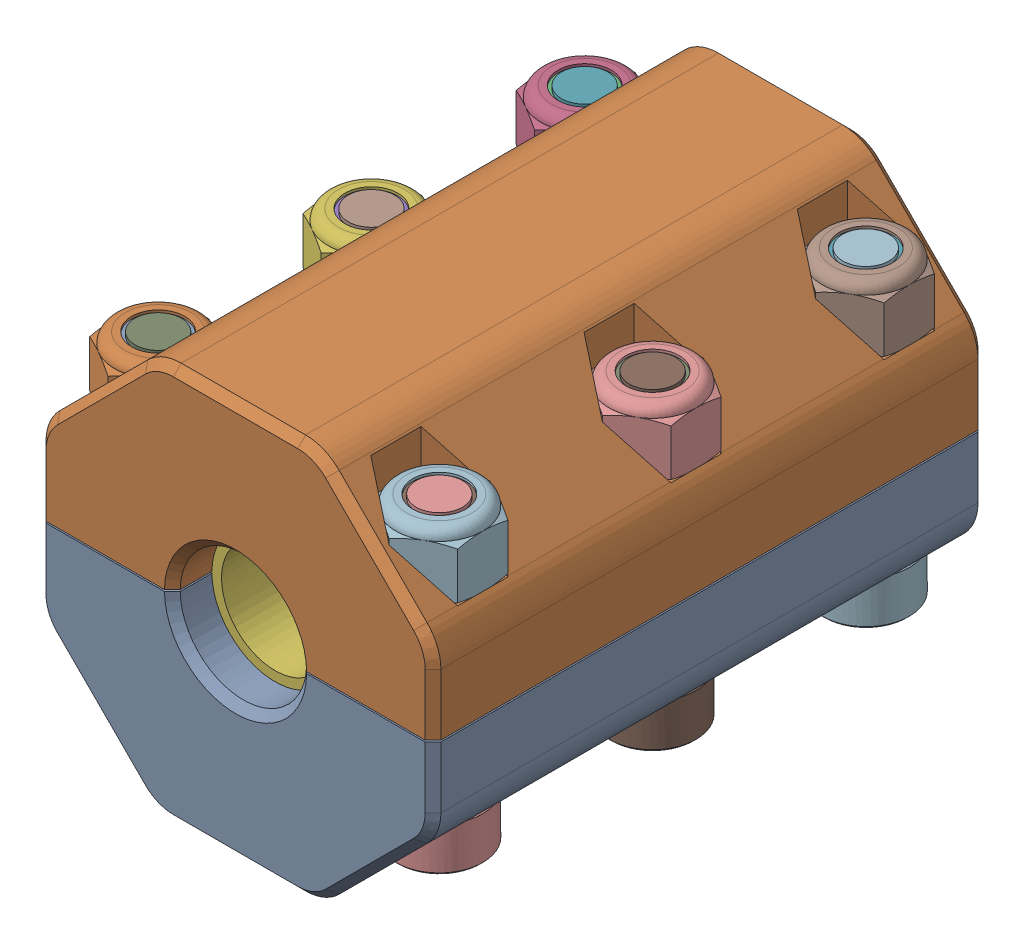
SolidWorks assembly 8mm Smooth to Threaded Shaft Coupler, configuration Default. Lengths in mm.
Overall size (25 25 35).
17 component instances, 6 part files, 0 mates.
Components (placement in the parent):
- 8mm Threaded to Smooth Coupler Shell A-1: 8mm Threaded to Smooth Coupler Shell A [Default] at origin size (25 12.45 35)
- 8mm Threaded to Smooth Coupler Shell B-1: 8mm Threaded to Smooth Coupler Shell B [Default] at origin size (25 12.45 35)
- 57485K67-1: 57485K67 [57485K67] at (0 0 6.5) x (-1 0 0) z (0 0 1) size (16 16 8)
- M8 x 1.25 Hex Nut-1: M8 x 1.25 Hex Nut [Default] at (0 0 20.75) size (13 15.01 6.5)
- M8 x 1.25 Hex Nut-2: M8 x 1.25 Hex Nut [Default] at (0 0 29.25) size (13 15.01 6.5)
- M3 x 0.5 Lock Nut-1: M3 x 0.5 Lock Nut [Default] at (8.9 6 4) x (1 0 0) z (0 1 0) size (5.5 6.35 4)
- M3 x 0.5 Lock Nut-2: M3 x 0.5 Lock Nut [Default] at (8.9 6 17.5) x (1 0 0) z (0 1 0) size (5.5 6.35 4)
- M3 x 0.5 Lock Nut-3: M3 x 0.5 Lock Nut [Default] at (8.9 6 31) x (1 0 0) z (0 1 0) size (5.5 6.35 4)
- M3 x 0.5 Lock Nut-4: M3 x 0.5 Lock Nut [Default] at (-8.9 6 31) x (1 0 0) z (0 1 0) size (5.5 6.35 4)
- M3 x 0.5 Lock Nut-5: M3 x 0.5 Lock Nut [Default] at (-8.9 6 4) x (1 0 0) z (0 1 0) size (5.5 6.35 4)
- M3 x 0.5 Lock Nut-6: M3 x 0.5 Lock Nut [Default] at (-8.9 6 17.5) x (1 0 0) z (0 1 0) size (5.5 6.35 4)
- M3 x 1 mm 16 mm Length Socket Head Screw-1: M3 x 1 mm 16 mm Length Socket Head Screw [Default] at (-8.9 -6 4) x (1 0 0) z (0 -1 0) size (5.5 5.5 19.14)
- M3 x 1 mm 16 mm Length Socket Head Screw-2: M3 x 1 mm 16 mm Length Socket Head Screw [Default] at (-8.9 -6 17.5) x (1 0 0) z (0 -1 0) size (5.5 5.5 19.14)
- M3 x 1 mm 16 mm Length Socket Head Screw-3: M3 x 1 mm 16 mm Length Socket Head Screw [Default] at (-8.9 -6 31) x (1 0 0) z (0 -1 0) size (5.5 5.5 19.14)
- M3 x 1 mm 16 mm Length Socket Head Screw-4: M3 x 1 mm 16 mm Length Socket Head Screw [Default] at (8.9 -6 31) x (1 0 0) z (0 -1 0) size (5.5 5.5 19.14)
- M3 x 1 mm 16 mm Length Socket Head Screw-5: M3 x 1 mm 16 mm Length Socket Head Screw [Default] at (8.9 -6 17.5) x (1 0 0) z (0 -1 0) size (5.5 5.5 19.14)
- M3 x 1 mm 16 mm Length Socket Head Screw-6: M3 x 1 mm 16 mm Length Socket Head Screw [Default] at (8.9 -6 4) x (1 0 0) z (0 -1 0) size (5.5 5.5 19.14)
